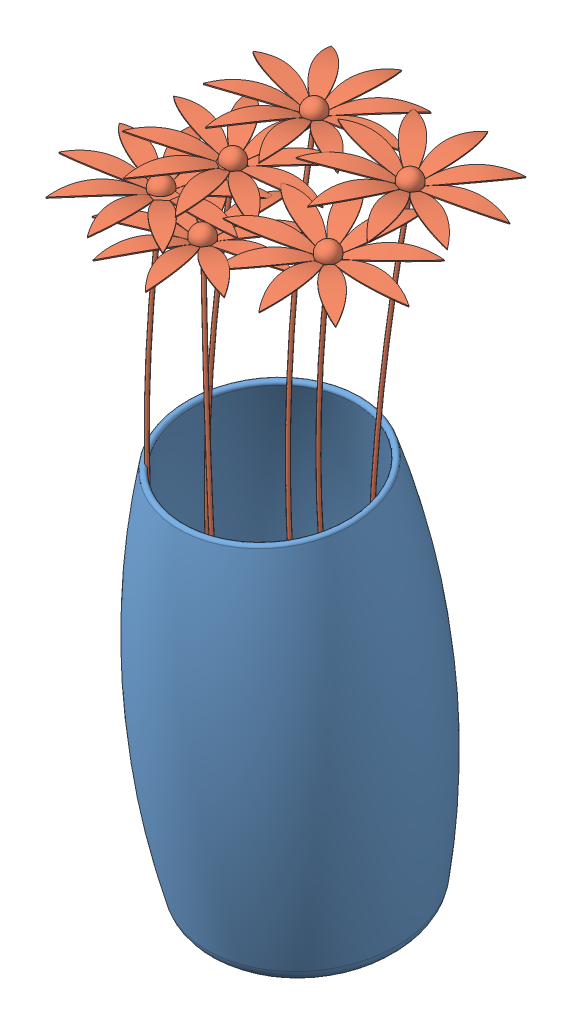
SolidWorks assembly flower vase, configuration Default. Lengths in mm.
Overall size (167.67 328.44 187.99).
7 component instances, 2 part files, 6 mates.
Components (placement in the parent):
- gol-2: gol [Default] at (-177.8528 -129.8724 -156.8458) x (0.820286 0.051105 -0.569666) z (0.571737 -0.100709 0.814232) size (113.91 196.07 113.91)
- f3-4: f3 [Default] at (-195.883 177.0245 -138.2919) x (0.995593 -0.049933 0.079376) z (-0.078067 0.027635 0.996565) size (78.78 312.42 77.59)
- f3-6: f3 [Default] at (-193.6734 180.4526 -175.3812) x (0.998188 -0.008035 0.05964) z (-0.05899 0.065416 0.996113) size (78.78 312.42 77.59)
- f3-8: f3 [Default] at (-136.2864 174.7559 -124.8496) x (0.97853 -0.069183 0.194145) z (-0.197429 -0.044233 0.979319) size (78.78 312.42 77.59)
- f3-9: f3 [Default] at (-204.48 174.1713 -112.3083) x (0.969757 -0.001794 0.244066) z (-0.243989 0.019016 0.969592) size (78.78 312.42 77.59)
- f3-10: f3 [Default] at (-175.7101 172.4649 -103.6816) x (0.810831 0.034925 -0.584237) z (0.583236 0.035147 0.811542) size (78.78 312.42 77.59)
- f3-11: f3 [Default] at (-142.4789 178.9754 -170.5393) x (0.994585 -0.084883 -0.059965) z (0.062713 0.030091 0.997578) size (78.78 312.42 77.59)
Mates (geometry in assembly coordinates):
- Tangent16: tangent: circle of gol-2; circle of f3-6
- Tangent17: tangent: circle of gol-2; circle of f3-10
- Tangent18: tangent: circle of gol-2; circle of f3-11
- Tangent21: tangent: circle of gol-2; circle of f3-8
- Coincident3: coincident: point of gol-2; circle of f3-4
- Coincident4: coincident: point of gol-2; circle of f3-9
